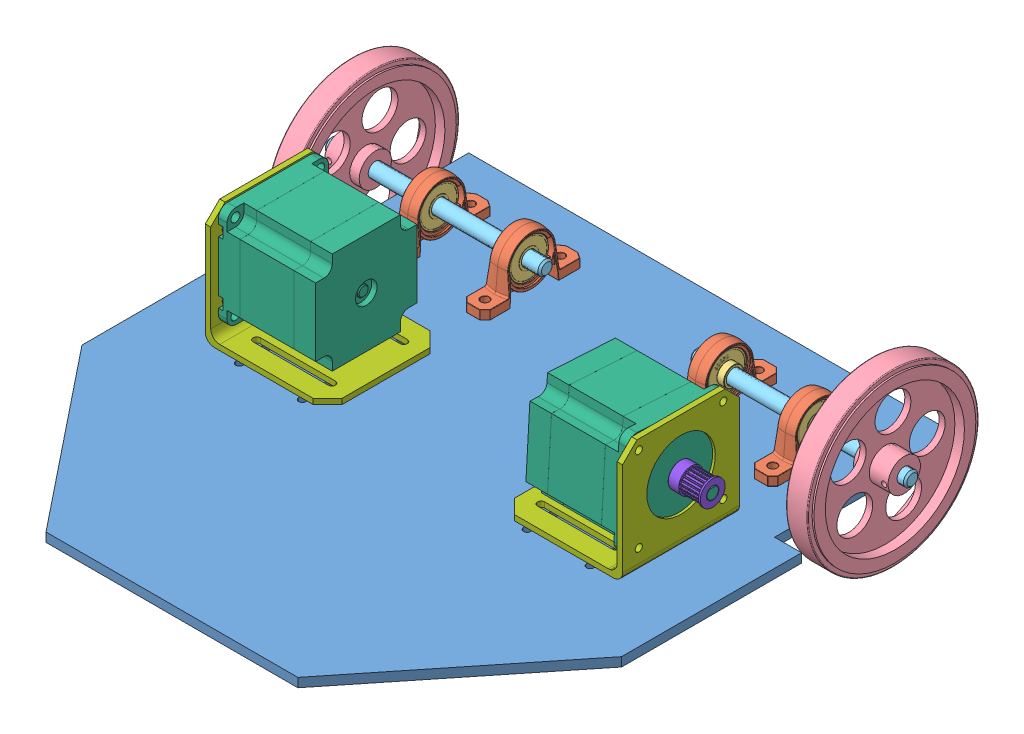
SolidWorks assembly assm, configuration 預設. Lengths in mm.
Overall size (323.2 106.74 303.37).
23 component instances, 8 part files, 28 mates.
Components (placement in the parent):
- base-1: base [預設] at (1.6455 -61.945 400) size (300 5 300)
- KP081-1: KP081 [預設] at (-103.3545 -56.945 297.7101) x (0 0 1) z (-1 0 0) size (55 40.89 13.95)
  - KP08_1-1: KP08_1 [預設] at (2.2899 16 0) size (55 40.89 13.19)
  - 608RS-1: 608RS [預設] at (2.2899 16 -3.5) x (0.16403 0.986455 0) z (0 0 1) size (22 22 10.85)
- KP081-2: KP081 [預設] at (-53.3545 -56.945 297.7101) x (0 0 1) z (-1 0 0) size (55 40.89 13.95)
  - KP08_1-1: KP08_1 [預設] at (2.2899 16 0) size (55 40.89 13.19)
  - 608RS-1: 608RS [預設] at (2.2899 16 -3.5) x (0.16403 0.986455 0) z (0 0 1) size (22 22 10.85)
- KP081-3: KP081 [預設] at (56.6455 -56.945 302.2899) x (0 0 -1) z (1 0 0) size (55 40.89 13.95)
  - KP08_1-1: KP08_1 [預設] at (2.2899 16 0) size (55 40.89 13.19)
  - 608RS-1: 608RS [預設] at (2.2899 16 -3.5) x (0.16403 0.986455 0) z (0 0 1) size (22 22 10.85)
- KP081-4: KP081 [預設] at (106.6455 -56.945 297.7101) x (0 0 1) z (-1 0 0) size (55 40.89 13.95)
  - KP08_1-1: KP08_1 [預設] at (2.2899 16 0) size (55 40.89 13.19)
  - 608RS-1: 608RS [預設] at (2.2899 16 -3.5) x (0.16403 0.986455 0) z (0 0 1) size (22 22 10.85)
- wheel_95mm-1: wheel_95mm [預設] at (-142.2672 -40.945 300) x (0 0.999674 -0.025514) z (0 0.025514 0.999674) size (95 19.2 95)
- wheel_95mm-2: wheel_95mm [預設] at (146.53 -40.945 300) x (0 -0.991194 -0.132416) z (0 -0.132416 0.991194) size (95 19.2 95)
- 8mm_rod_150mm-1: 8mm_rod_150mm [預設] at (-159.9545 -40.945 300) x (0 -1 0) z (0 0 1) size (8 120 8)
- 8mm_rod_150mm-2: 8mm_rod_150mm [預設] at (43.2455 -40.945 300) x (0 -0.989568 -0.144069) z (0 -0.144069 0.989568) size (8 120 8)
- 57motor-1: 57motor [預設] at (-112.4038 -20.945 381.9031) x (0 0 1) z (-1 0 0) size (56.4 56.4 74.6)
- 57motor-2: 57motor [預設] at (113.5734 -20.945 381.9031) x (0 -0.0584 -0.998293) z (1 0 0) size (56.4 56.4 74.6)
- mount nema 23-1: mount nema 23 [預設] at (-115.4038 -24.445 381.9031) x (0 0 -1) z (0 -1 0) size (65 68 65)
- mount nema 23-2: mount nema 23 [預設] at (116.5734 -24.445 381.9031) x (0 0 1) z (0 -1 0) size (65 68 65)
- gt2_20th-1: gt2_20th [預設] at (-115.0038 -20.945 381.9031) x (0 0 1) z (-1 0 0) size (13.8 13.8 18)
- gt2_20th-2: gt2_20th [預設] at (116.1734 -20.945 381.9031) x (0 0 -1) z (1 0 0) size (13.8 13.8 18)
Mates (geometry in assembly coordinates):
- 同軸心11: concentric anti-aligned: cylinder of base-1 through (-53.3545 -56.945 279) axis (0 -1 0) radius 2.25; cylinder of KP081-2/KP08_1-1 through (-53.3545 -56.945 279) axis (0 1 0) radius 2.25
- 同軸心12: concentric anti-aligned: cylinder of base-1 through (-53.3545 -56.945 321) axis (0 -1 0) radius 2.25; cylinder of KP081-2/KP08_1-1 through (-53.3545 -56.945 321) axis (0 1 0) radius 2.25
- 同軸心13: concentric anti-aligned: cylinder of base-1 through (-103.3545 -56.945 279) axis (0 -1 0) radius 2.25; cylinder of KP081-1/KP08_1-1 through (-103.3545 -56.945 279) axis (0 1 0) radius 2.25
- 同軸心14: concentric anti-aligned: cylinder of base-1 through (-103.3545 -56.945 321) axis (0 -1 0) radius 2.25; cylinder of KP081-1/KP08_1-1 through (-103.3545 -56.945 321) axis (0 1 0) radius 2.25
- 同軸心15: concentric anti-aligned: cylinder of base-1 through (56.6455 -56.945 321) axis (0 -1 0) radius 2.25; cylinder of KP081-3/KP08_1-1 through (56.6455 -56.945 321) axis (0 1 0) radius 2.25
- 同軸心16: concentric anti-aligned: cylinder of base-1 through (56.6455 -56.945 279) axis (0 -1 0) radius 2.25; cylinder of KP081-3/KP08_1-1 through (56.6455 -56.945 279) axis (0 1 0) radius 2.25
- 同軸心17: concentric anti-aligned: cylinder of base-1 through (106.6455 -56.945 321) axis (0 -1 0) radius 2.25; cylinder of KP081-4/KP08_1-1 through (106.6455 -56.945 321) axis (0 1 0) radius 2.25
- 同軸心18: concentric anti-aligned: cylinder of base-1 through (106.6455 -56.945 279) axis (0 -1 0) radius 2.25; cylinder of KP081-4/KP08_1-1 through (106.6455 -56.945 279) axis (0 1 0) radius 2.25
- 同軸心19: concentric anti-aligned: cylinder of KP081-1/608RS-1 through (-106.8545 -40.945 300) axis (1 0 0) radius 4; cylinder of 8mm_rod_150mm-1 through (-39.9545 -40.945 300) axis (-1 0 0) radius 4
- 平行相距1: distance = 10 mm aligned: plane of 8mm_rod_150mm-1 through (-39.9545 -40.945 300) normal (1 0 0); plane of KP081-2/608RS-1 through (-49.9545 -40.945 300) normal (1 0 0)
- 同軸心20: concentric anti-aligned: cylinder of KP081-4/608RS-1 through (103.1455 -40.945 300) axis (1 0 0) radius 4; cylinder of 8mm_rod_150mm-2 through (163.2455 -40.945 300) axis (-1 0 0) radius 4
- 平行相距2: distance = 10 mm aligned: plane of 8mm_rod_150mm-2 through (43.2455 -40.945 300) normal (-1 0 0); plane of KP081-3/608RS-1 through (53.2455 -40.945 300) normal (-1 0 0)
- 同軸心21: concentric anti-aligned: cylinder of wheel_95mm-1 through (-149.2672 -40.945 300) axis (1 0 0) radius 4; cylinder of 8mm_rod_150mm-1 through (-39.9545 -40.945 300) axis (-1 0 0) radius 4
- 同軸心22: concentric anti-aligned: cylinder of base-1 through (-103.3545 -56.945 279) axis (0 -1 0) radius 2.25; cylinder of KP081-1/KP08_1-1 through (-103.3545 -56.945 279) axis (0 1 0) radius 2.25
- 重合/共線/共點8: coincident anti-aligned: plane of base-1 through (1.6455 -56.945 400) normal (0 1 0); plane of KP081-1/KP08_1-1 through (-109.8545 -56.945 300) normal (0 -1 0)
- 重合/共線/共點10: coincident anti-aligned: plane of base-1 through (1.6455 -56.945 400) normal (0 1 0); plane of KP081-4/KP08_1-1 through (100.1455 -56.945 300) normal (0 -1 0)
- 同軸心23: concentric aligned: cylinder of wheel_95mm-2 through (153.53 -40.945 300) axis (-1 0 0) radius 4; cylinder of 8mm_rod_150mm-2 through (163.2455 -40.945 300) axis (-1 0 0) radius 4
- 重合/共線/共點14: coincident anti-aligned: plane of base-1 through (1.6455 -56.945 400) normal (0 1 0); plane of mount nema 23-1 through (-112.4038 -56.945 414.4031) normal (0 -1 0)
- 重合/共線/共點15: coincident anti-aligned: plane of base-1 through (1.6455 -56.945 400) normal (0 1 0); plane of mount nema 23-2 through (113.5734 -56.945 349.4031) normal (0 -1 0)
- 重合/共線/共點16: coincident aligned: plane of mount nema 23-1 through (-112.4038 8.055 414.4031) normal (0 0 1); plane of mount nema 23-2 through (113.5734 8.055 414.4031) normal (0 0 1)
- 重合/共線/共點19: coincident: plane of 57motor-1 through (-112.4038 7.255 410.1031) normal (-1 0 0); plane of mount nema 23-1 through (-112.4038 -24.445 381.9031) normal (1 0 0)
- 重合/共線/共點20: coincident anti-aligned: plane of 57motor-2 through (113.5734 5.56 352.1043) normal (1 0 0); plane of mount nema 23-2 through (113.5734 -24.445 381.9031) normal (-1 0 0)
- 同軸心36: concentric anti-aligned: cylinder of 57motor-1 through (-114.0038 -20.945 381.9031) axis (1 0 0) radius 19; cylinder of mount nema 23-1 through (-112.4038 -20.945 381.9031) axis (-1 0 0) radius 19.05
- 同軸心37: concentric anti-aligned: cylinder of 57motor-2 through (115.1734 -20.945 381.9031) axis (-1 0 0) radius 19; cylinder of mount nema 23-2 through (113.5734 -20.945 381.9031) axis (1 0 0) radius 19.05
- 同軸心38: concentric anti-aligned: cylinder of 57motor-1 through (-133.0038 -20.945 381.9031) axis (1 0 0) radius 3.175; cylinder of gt2_20th-1 through (-115.0038 -20.945 381.9031) axis (-1 0 0) radius 3.175
- 重合/共線/共點21: coincident aligned: plane of 57motor-1 through (-133.0038 -20.945 381.9031) normal (-1 0 0); plane of gt2_20th-1 through (-133.0038 -20.945 381.9031) normal (-1 0 0)
- 同軸心39: concentric anti-aligned: cylinder of 57motor-2 through (134.1734 -20.945 381.9031) axis (-1 0 0) radius 3.175; cylinder of gt2_20th-2 through (116.1734 -20.945 381.9031) axis (1 0 0) radius 3.175
- 重合/共線/共點22: coincident aligned: plane of 57motor-2 through (134.1734 -20.945 381.9031) normal (1 0 0); plane of gt2_20th-2 through (134.1734 -20.945 381.9031) normal (1 0 0)
